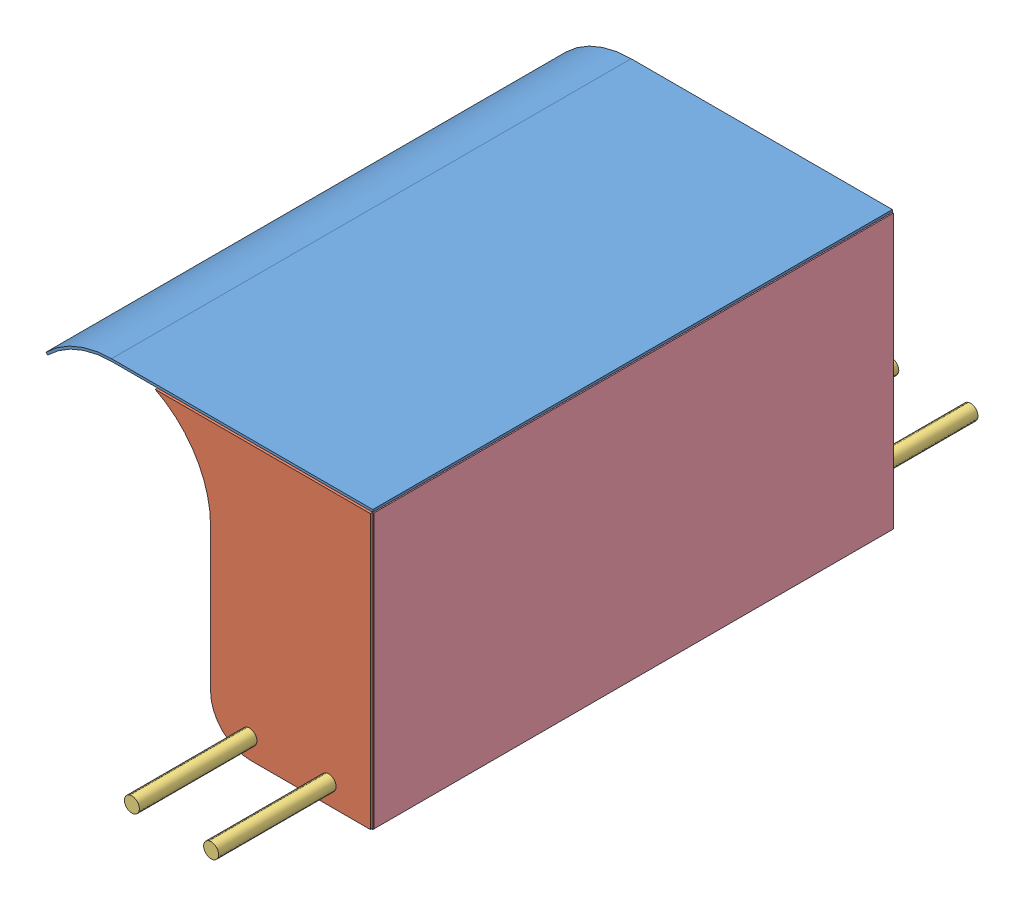
SolidWorks assembly 600-LipLower, configuration Default. Lengths in mm.
Overall size (208.43 176.15 482.6).
7 component instances, 5 part files, 13 mates.
Components (placement in the parent):
- 601-PlateCurved-1: 601-PlateCurved [Default] at origin size (207.68 18.31 330.2)
- 602-PlateSide-1: 602-PlateSide [Default] at origin size (136.78 173.9 1.5)
- 602-PlateSide-2: 602-PlateSide [Default] at (0 0 -331.7) size (136.78 173.9 1.5) (suppressed, hidden)
- 103-RodYokes-1: 103-RodYokes [Default] at (-88.6875 638.53 0) size (9.53 9.52 482.6)
- 103-RodYokes-2: 103-RodYokes [Default] at (-139.0125 638.53 0) size (9.53 9.52 482.6)
- 603-PlateBack-1: 603-PlateBack [Default] at (-418.175 0 0) x (0 0 -1) z (1 0 0) size (330.2 173.9 1.5)
- 605-PlateCurveCover-1: 605-PlateCurveCover [Default] at (-494.375 788.53 0) x (0 0 -1) z (-1 0 0) size (330.2 175.32 137.12)
Mates (geometry in assembly coordinates):
- InPlace1: in place: plane of ?
- Coincident1: coincident aligned: plane of 601-PlateCurved-1; plane of ?
- Coincident2: coincident aligned: plane of ? through (0 0 0) normal (0 1 0)
- Coincident3: coincident anti-aligned: plane of ? through (0 0 0) normal (1 0 0)
- Concentric1: concentric aligned: cylinder of 602-PlateSide-1 through (-444.7375 801.23 166.6) axis (0 0 -1) radius 4.7625; cylinder of 103-RodYokes-1 through (-444.7375 801.23 241.3) axis (0 0 -1) radius 4.7625
- Coincident4: coincident aligned: plane of 103-RodYokes-1 through (-88.6875 638.53 0) normal (0 0 1); plane of assembly through (0 0 0) normal (0 0 1)
- Parallel1: parallel aligned: plane of 103-RodYokes-1 through (-88.6875 638.53 0) normal (1 0 0); plane of assembly through (0 0 0) normal (1 0 0)
- Coincident6: coincident aligned: plane of 103-RodYokes-1 through (-444.7375 801.23 241.3) normal (0 0 1); plane of 103-RodYokes-2 through (-495.0625 801.23 241.3) normal (0 0 1)
- Concentric2: concentric aligned: cylinder of 602-PlateSide-2 through (-495.0625 801.23 -165.1) axis (0 0 -1) radius 4.7625; cylinder of 103-RodYokes-2 through (-495.0625 801.23 241.3) axis (0 0 -1) radius 4.7625
- InPlace2: in place: plane of ? through (-418.175 963.93 165.1) normal (1 0 0); unknown of 603-PlateBack-1
- Coincident7: coincident aligned: plane of 601-PlateCurved-1; plane of 603-PlateBack-1
- Coincident8: coincident aligned: moOrthogonalPlaneRef_w of 601-PlateCurved-1 through (-1000 -418.175 0) axis (0 0 1); plane of 603-PlateBack-1
- Coincident9: coincident anti-aligned: moOrthogonalPlaneRef_w of 601-PlateCurved-1 through (-418.175 0 0) axis (0 0 1); plane of 603-PlateBack-1 through (-418.175 0 0) normal (0 0 -1)
